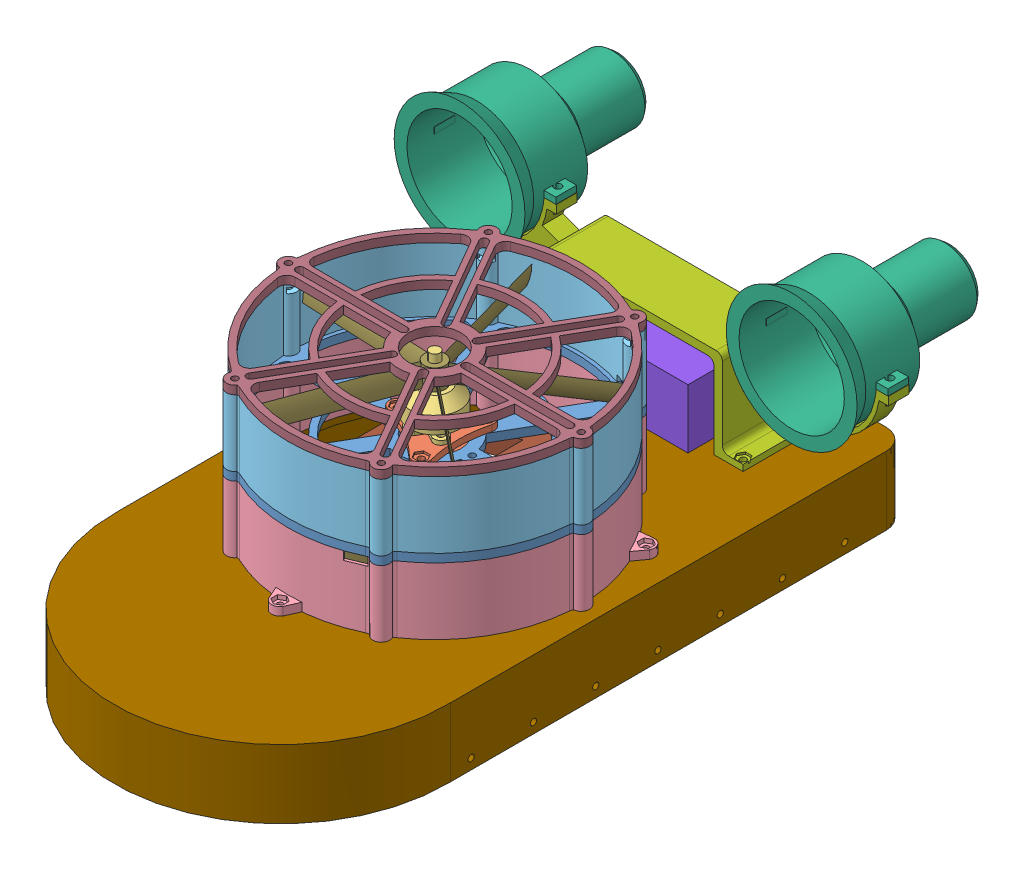
SolidWorks assembly 气垫风扇装配体, configuration 默认. Lengths in mm.
Overall size (379.83 126.36 395.39).
18 component instances, 14 part files, 63 mates.
Components (placement in the parent):
- 气垫电机固定座(无挡板)-1: 气垫电机固定座(无挡板) [默认] at (-6.3038 -0.0437 147) size (149 4 141.13)
- 电机固定片-1: 电机固定片 [默认] at (-6.3038 3.9563 147) x (0.866025 0 0.5) z (-0.5 0 0.866025) size (39.18 3 35)
- 电机固定片-2: 电机固定片 [默认] at (-6.3038 -0.0437 147) x (0 0 -1) z (-1 0 0) size (39.18 3 35)
- 2306-1: 2306 [默认] at (-6.3038 6.9563 147) x (0.866025 0 0.5) z (-0.5 0 0.866025) size (24 32 24)
- 2306-2: 2306 [默认] at (-6.3038 -3.0437 147) x (1 0 0) z (0 0 -1) size (24 32 24)
- 气垫电机固定筒-2: 气垫电机固定筒 [默认] at (-6.3038 -13.5437 147) x (-0.5 0 -0.866025) z (-0.866025 0 0.5) size (149 32 149.13)
- 气垫电机固定筒(上筒)-2: 气垫电机固定筒(上筒) [默认] at (-6.3038 22.4563 147) x (-0.5 0 0.866025) z (0.866025 0 0.5) size (149 32 141.13)
- EDF50涵道电机-1: EDF50涵道电机 [默认] at (-85.8702 25.8177 -16.8028) x (-1 0 0) z (0 0 -1) size (66.7 63 76)
- 涵道电机与电池固定底座-1: 涵道电机与电池固定底座 [默认] at (-6.3038 -31.6989 37.4797) x (0 0 -1) z (1 0 0) size (30 56.36 228)
- 电池-1: 电池 [默认] at (-9.8038 -17.7937 58.033) x (1 0 0) z (0 1 0) size (73 35 28.5)
- EDF50涵道电机-2: EDF50涵道电机 [默认] at (74.1298 25.8177 -16.8028) x (-1 0 0) z (0 0 -1) size (66.7 63 76)
- 零件7^气垫风扇装配体-1: 零件7^气垫风扇装配体 [默认] at (-6.3038 -35.0437 147) x (-0.5 0 -0.866025) z (0 -1 0) (virtual)
- 气垫船上底盘-3: 气垫船上底盘 [默认] at (-6.3038 -35.0437 147) x (0.5 0 -0.866025) z (0 1 0) size (308.44 256.54 33)
- 气垫下固定片-1: 气垫下固定片 [默认] at (-6.5038 -72.0437 132.1728) x (-0.5 0 0.866025) z (0 1 0) size (173.56 140.62 4)
- 气垫下底盘-4: 气垫下底盘 [默认] at (-6.5038 -52.0437 147) x (-0.5 0 -0.866025) z (0 -1 0) size (300.04 248.14 10)
- 桨叶模拟-1: 桨叶模拟 [默认] at (-6.3038 24.9563 147) x (-0.963312 0 0.268384) z (-0.268384 0 -0.963312) size (125.21 10 119.08)
- 桨叶模拟-2: 桨叶模拟 [默认] at (-6.3038 -21.0437 147) x (0.837169 0 0.546944) z (0.546944 0 -0.837169) size (125.21 10 119.08)
- 气垫电机挡板-1: 气垫电机挡板 [默认] at (-6.3038 35.9563 147) x (0.5 0 0.866025) z (-0.866025 0 0.5) size (149 4 141.13)
Mates (geometry in assembly coordinates):
- 重合1: coincident anti-aligned: plane of 气垫电机固定座(无挡板)-1 through (-6.3038 3.9563 147) normal (0 1 0); plane of 电机固定片-1 through (-18.9797 3.9563 109.4562) normal (0 -1 0)
- 同心1: concentric aligned: cylinder of 气垫电机固定座(无挡板)-1 through (2.6962 8.9563 162.5885) axis (0 -1 0) radius 1.5; cylinder of 电机固定片-1 through (2.6962 6.9563 162.5885) axis (0 -1 0) radius 1.5
- 同心2: concentric aligned: cylinder of 气垫电机固定座(无挡板)-1 through (2.6962 8.9563 131.4115) axis (0 -1 0) radius 1.5; cylinder of 电机固定片-1 through (2.6962 6.9563 131.4115) axis (0 -1 0) radius 1.5
- 重合2: coincident anti-aligned: plane of 气垫电机固定座(无挡板)-1 through (-6.3038 -0.0437 147) normal (0 -1 0); plane of 电机固定片-2 through (19.8722 -0.0437 176.7496) normal (0 1 0)
- 同心3: concentric anti-aligned: cylinder of 气垫电机固定座(无挡板)-1 through (-15.3038 8.9563 162.5885) axis (0 -1 0) radius 1.5; cylinder of 电机固定片-2 through (-15.3038 -3.0437 162.5885) axis (0 1 0) radius 1.5
- 同心4: concentric anti-aligned: cylinder of 气垫电机固定座(无挡板)-1 through (11.6962 8.9563 147) axis (0 -1 0) radius 1.5; cylinder of 电机固定片-2 through (11.6962 -3.0437 147) axis (0 1 0) radius 1.5
- 重合3: coincident anti-aligned: plane of 电机固定片-1 through (-18.9797 6.9563 109.4562) normal (0 1 0); plane of 2306-1 through (-6.3038 6.9563 147) normal (0 -1 0)
- 同心5: concentric aligned: cylinder of 电机固定片-1 through (-10.3038 6.9563 153.9282) axis (0 -1 0) radius 1.5; cylinder of 2306-1 through (-10.3038 8.9563 153.9282) axis (0 -1 0) radius 1.5
- 同心6: concentric aligned: cylinder of 电机固定片-1 through (0.6244 6.9563 151) axis (0 -1 0) radius 1.5; cylinder of 2306-1 through (0.6244 8.9563 151) axis (0 -1 0) radius 1.5
- 重合4: coincident anti-aligned: plane of 电机固定片-2 through (19.8722 -3.0437 176.7496) normal (0 -1 0); plane of 2306-2 through (-6.3038 -3.0437 147) normal (0 1 0)
- 同心7: concentric aligned: cylinder of 电机固定片-2 through (-14.3038 -3.0437 147) axis (0 1 0) radius 1.5; cylinder of 2306-2 through (-14.3038 -5.0437 147) axis (0 1 0) radius 1.5
- 同心8: concentric aligned: cylinder of 电机固定片-2 through (1.6962 -3.0437 147) axis (0 1 0) radius 1.5; cylinder of 2306-2 through (1.6962 -5.0437 147) axis (0 1 0) radius 1.5
- 重合5: coincident anti-aligned: plane of 气垫电机固定座(无挡板)-1 through (-6.3038 -0.0437 147) normal (0 -1 0); plane of 气垫电机固定筒-1 through (-6.3038 -0.0437 147) normal (0 1 0)
- 同心9: concentric aligned: cylinder of 气垫电机固定座(无挡板)-1 through (-41.5538 3.9563 85.9452) axis (0 -1 0) radius 1.5; cylinder of 气垫电机固定筒-1 through (-41.5538 6.4563 85.9452) axis (0 -1 0) radius 1.5
- 同心10: concentric aligned: cylinder of 气垫电机固定座(无挡板)-1 through (28.9462 3.9563 85.9452) axis (0 -1 0) radius 1.5; cylinder of 气垫电机固定筒-1 through (28.9462 6.4563 85.9452) axis (0 -1 0) radius 1.5
- 同心11: concentric aligned: cylinder of 气垫电机固定座(无挡板)-1 through (64.1962 3.9563 147) axis (0 -1 0) radius 1.5; cylinder of 气垫电机固定筒(上筒)-2 through (64.1962 42.4563 147) axis (0 -1 0) radius 1.5
- 同心12: concentric aligned: cylinder of 气垫电机固定座(无挡板)-1 through (28.9462 3.9563 85.9452) axis (0 -1 0) radius 1.5; cylinder of 气垫电机固定筒(上筒)-2 through (28.9462 42.4563 85.9452) axis (0 -1 0) radius 1.5
- 重合6: coincident anti-aligned: plane of 气垫电机固定座(无挡板)-1 through (-6.3038 3.9563 147) normal (0 1 0); plane of 气垫电机固定筒(上筒)-2 through (-6.3038 3.9563 147) normal (0 -1 0)
- 重合7: coincident anti-aligned: plane of 气垫电机固定座(无挡板)-1 through (-6.3038 -0.0437 147) normal (0 -1 0); circle of 气垫电机固定筒-2
- 同心13: concentric anti-aligned: cylinder of 气垫电机固定座(无挡板)-1 through (28.9462 3.9563 208.0548) axis (0 -1 0) radius 1.5; cylinder of 气垫电机固定筒-2 through (28.9462 -32.0437 208.0548) axis (0 1 0) radius 1.5
- 同心14: concentric anti-aligned: cylinder of 气垫电机固定座(无挡板)-1 through (-41.5538 3.9563 208.0548) axis (0 -1 0) radius 1.5; cylinder of 气垫电机固定筒-2 through (-41.5538 -32.0437 208.0548) axis (0 1 0) radius 1.5
- 在位1: in place: plane of 气垫电机固定筒-2 through (-6.3038 -32.0437 147) normal (0 -1 0); plane of ? through (0 -32.0437 0) normal (0 -1 0); moOrthogonalPlaneRef_w of 气垫电机固定筒-2 through (-6.3038 -32.0437 147) normal (0 -1 0); plane of ? through (0 -32.0437 0) normal (0 0 -1); plane of 气垫电机固定筒-2 through (-6.3038 -32.0437 147) normal (0 -1 0); plane of ? through (0 -32.0437 0) normal (-1 0 0); plane of 气垫电机固定筒-2 through (-6.3038 -32.0437 147) normal (0 -1 0); unknown of ?
- 重合8: coincident aligned: plane of 气垫电机固定筒-2; plane of ?
- 重合9: coincident aligned: moOrthogonalPlaneRef_w of 气垫电机固定筒-2 through (-6.3038 -32.0437 147) normal (0.866025 0 -0.5); plane of 气垫船上底盘-1 through (-6.3038 -32.0437 147) normal (0.866025 0 -0.5)
- 重合10: coincident anti-aligned: moOrthogonalPlaneRef_w of 气垫电机固定筒-2 through (-6.3038 -32.0437 147) normal (0.5 0 0.866025); plane of 气垫船上底盘-1 through (-6.3038 -32.0437 147) normal (-0.5 0 -0.866025)
- 同心15: concentric aligned: cylinder of 气垫船上底盘-1 through (44.6962 -42.0437 25.4797) axis (0 1 0) radius 1.5; cylinder of 涵道电机与电池固定底座-1 through (44.6962 -40.0437 25.4797) axis (0 1 0) radius 1.5
- 重合11: coincident anti-aligned: plane of 气垫船上底盘-1 through (63.6962 -32.0437 9.4797) normal (0 1 0); plane of 涵道电机与电池固定底座-1 through (33.6962 -32.0437 52.4797) normal (0 -1 0)
- 同心16: concentric aligned: cylinder of 气垫船上底盘-1 through (44.6962 -42.0437 49.4797) axis (0 1 0) radius 1.5; cylinder of 涵道电机与电池固定底座-1 through (44.6962 -40.0437 49.4797) axis (0 1 0) radius 1.5
- 同心17: concentric aligned: cylinder of EDF50涵道电机-1 through (-56.6038 24.3177 37.4797) axis (0 1 0) radius 1.75; cylinder of 涵道电机与电池固定底座-1 through (-56.6038 13.3177 37.4797) axis (0 1 0) radius 1.5
- 重合12: coincident anti-aligned: plane of EDF50涵道电机-1 through (-85.8702 24.3177 -16.8028) normal (0 -1 0); plane of 涵道电机与电池固定底座-1 through (-114.0538 24.3177 42.4797) normal (0 1 0)
- 重合13: coincident anti-aligned: plane of 涵道电机与电池固定底座-1 through (101.4462 24.3177 42.4797) normal (0 1 0); plane of EDF50涵道电机-2 through (74.1298 24.3177 -16.8028) normal (0 -1 0)
- 同心19: concentric aligned: cylinder of 涵道电机与电池固定底座-1 through (103.3962 13.3177 37.4797) axis (0 1 0) radius 1.5; cylinder of EDF50涵道电机-2 through (103.3962 24.3177 37.4797) axis (0 1 0) radius 1.75
- 平行2: parallel aligned: plane of 涵道电机与电池固定底座-1 through (107.6962 24.3177 42.4797) normal (1 0 0); plane of EDF50涵道电机-2 through (107.4798 24.3177 42.4797) normal (1 0 0)
- 平行3: parallel aligned: plane of EDF50涵道电机-1 through (-119.2202 24.3177 42.4797) normal (-1 0 0); plane of 涵道电机与电池固定底座-1 through (-120.3038 24.3177 42.4797) normal (-1 0 0)
- 重合16: coincident anti-aligned: plane of 气垫船上底盘-1 through (63.6962 -32.0437 9.4797) normal (0 1 0); plane of 电池-1 through (-46.3038 -32.0437 23.033) normal (0 -1 0)
- 重合17: coincident anti-aligned: plane of 涵道电机与电池固定底座-1 through (-46.3038 -32.0437 52.4797) normal (1 0 0); plane of 电池-1 through (-46.3038 -32.0437 23.033) normal (-1 0 0)
- 在位2: in place: plane of ? through (63.6962 -35.0437 9.4797) normal (0 -1 0); plane of ? through (0 -35.0437 0) normal (0 -1 0); plane of ? through (63.6962 -35.0437 9.4797) normal (0 -1 0); plane of ? through (0 -35.0437 0) normal (0 0 -1); plane of ? through (63.6962 -35.0437 9.4797) normal (0 -1 0); plane of ? through (0 -35.0437 0) normal (-1 0 0); plane of ? through (63.6962 -35.0437 9.4797) normal (0 -1 0); unknown of 零件7^气垫风扇装配体-1
- 重合18: coincident aligned: plane of ?; plane of 零件7^气垫风扇装配体-1
- 重合19: coincident aligned: moOrthogonalPlaneRef_w of 气垫船上底盘-1 through (-6.3038 -35.0437 147) normal (0.866025 0 -0.5); plane of 零件7^气垫风扇装配体-1 through (-6.3038 -35.0437 147) normal (0.866025 0 -0.5)
- 重合20: coincident anti-aligned: moOrthogonalPlaneRef_w of 气垫船上底盘-1 through (-6.3038 -35.0437 147) normal (0.5 0 0.866025); plane of 零件7^气垫风扇装配体-1 through (-6.3038 -35.0437 147) normal (-0.5 0 -0.866025)
- 重合21: coincident anti-aligned: plane of 气垫电机固定筒-2 through (-6.3038 -32.0437 147) normal (0 -1 0); plane of 气垫船上底盘-2 through (-76.3038 -32.0437 9.4797) normal (0 1 0)
- 同心20: concentric anti-aligned: cylinder of 气垫电机固定筒-2 through (-6.3038 -32.0437 221.5638) axis (0 1 0) radius 1.5; cylinder of 气垫船上底盘-2 through (-6.3038 -32.0437 221.5638) axis (0 -1 0) radius 1.5
- 同心21: concentric anti-aligned: cylinder of 气垫电机固定筒-2 through (-70.8779 -32.0437 109.7181) axis (0 1 0) radius 1.5; cylinder of 气垫船上底盘-2 through (-70.8779 -32.0437 109.7181) axis (0 -1 0) radius 1.5
- 重合22: coincident anti-aligned: plane of 气垫电机固定筒-2 through (-6.3038 -32.0437 147) normal (0 -1 0); plane of 气垫船上底盘-3 through (-76.3038 -32.0437 9.4797) normal (0 1 0)
- 同心22: concentric anti-aligned: cylinder of 气垫电机固定筒-2 through (-6.3038 -32.0437 221.5638) axis (0 1 0) radius 1.5; cylinder of 气垫船上底盘-3 through (-6.3038 -32.0437 221.5638) axis (0 -1 0) radius 1.5
- 同心23: concentric anti-aligned: cylinder of 气垫电机固定筒-2 through (58.2704 -32.0437 109.7181) axis (0 1 0) radius 1.5; cylinder of 气垫船上底盘-3 through (58.2704 -32.0437 109.7181) axis (0 -1 0) radius 1.5
- 重合23: coincident: plane of 气垫船上底盘-3 through (69.6962 -65.0437 9.4797) normal (-1 0 0); plane of 气垫下底盘-3 through (69.6962 -55.0437 9.4797) normal (1 0 0)
- 同心24: concentric: cylinder of 气垫船上底盘-3 through (177.208 -60.0437 29.4797) axis (-1 0 0) radius 1.5; cylinder of 气垫下底盘-3 through (183.0962 -60.0437 29.4797) axis (-1 0 0) radius 1.5
- 同心25: concentric aligned: cylinder of 气垫船上底盘-3 through (177.208 -60.0437 59.4797) axis (-1 0 0) radius 1.5; cylinder of 气垫下底盘-3 through (183.0962 -60.0437 59.4797) axis (-1 0 0) radius 1.5
- 重合24: coincident anti-aligned: plane of 气垫下底盘-3 through (-6.1038 -65.0437 147) normal (0 -1 0); plane of 气垫下固定片-1 through (-6.5038 -69.0437 132.1728) normal (0 -1 0)
- 同心26: concentric anti-aligned: cylinder of 气垫船上底盘-3 through (177.208 -60.0437 29.4797) axis (-1 0 0) radius 1.5; cylinder of 气垫下底盘-4 through (-195.7038 -60.0437 29.4797) axis (1 0 0) radius 1.5
- 重合25: coincident anti-aligned: plane of 气垫船上底盘-3 through (-82.3038 -65.0437 219.5253) normal (1 0 0); plane of 气垫下底盘-4 through (-82.3038 -65.0437 9.4797) normal (-1 0 0)
- 同心27: concentric anti-aligned: cylinder of 气垫船上底盘-3 through (177.208 -60.0437 59.4797) axis (-1 0 0) radius 1.5; cylinder of 气垫下底盘-4 through (-195.7038 -60.0437 59.4797) axis (1 0 0) radius 1.5
- 重合26: coincident anti-aligned: plane of 气垫下固定片-1 through (-6.5038 -65.0437 132.1728) normal (0 1 0); plane of 气垫下底盘-4 through (-6.5038 -65.0437 221.28) normal (0 -1 0)
- 同心28: concentric anti-aligned: cylinder of 气垫下固定片-1 through (-28.5038 -324.0437 63.0864) axis (0 1 0) radius 1.5; cylinder of 气垫下底盘-4 through (-28.5038 199.9563 63.0864) axis (0 -1 0) radius 1.5
- 同心29: concentric anti-aligned: cylinder of 气垫下固定片-1 through (11.4962 -324.0437 63.0864) axis (0 1 0) radius 1.5; cylinder of 气垫下底盘-4 through (11.4962 199.9563 63.0864) axis (0 -1 0) radius 1.5
- 同心30: concentric aligned: cylinder of 2306-1 through (-6.3038 38.9563 147) axis (0 -1 0) radius 2.5; cylinder of 桨叶模拟-1 through (-6.3038 34.9563 147) axis (0 -1 0) radius 2.5
- 重合27: coincident anti-aligned: plane of 2306-1 through (-6.3038 24.9563 147) normal (0 1 0); plane of 桨叶模拟-1 through (-6.3038 24.9563 147) normal (0 -1 0)
- 同心31: concentric aligned: cylinder of 2306-2 through (-6.3038 -35.0437 147) axis (0 1 0) radius 2.5; cylinder of 桨叶模拟-2 through (-6.3038 -31.0437 147) axis (0 1 0) radius 2.5
- 重合28: coincident anti-aligned: plane of 2306-2 through (-6.3038 -21.0437 147) normal (0 -1 0); plane of 桨叶模拟-2 through (-6.3038 -21.0437 147) normal (0 1 0)
- 重合29: coincident anti-aligned: plane of 气垫电机固定筒(上筒)-2 through (-6.3038 35.9563 147) normal (0 1 0); plane of 气垫电机挡板-1 through (-6.3038 35.9563 147) normal (0 -1 0)
- 同心32: concentric aligned: cylinder of 气垫电机固定筒(上筒)-2 through (28.9462 42.4563 208.0548) axis (0 -1 0) radius 1.5; cylinder of 气垫电机挡板-1 through (28.9462 39.9563 208.0548) axis (0 -1 0) radius 1.5
- 同心33: concentric aligned: cylinder of 气垫电机固定筒(上筒)-2 through (64.1962 42.4563 147) axis (0 -1 0) radius 1.5; cylinder of 气垫电机挡板-1 through (64.1962 39.9563 147) axis (0 -1 0) radius 1.5
